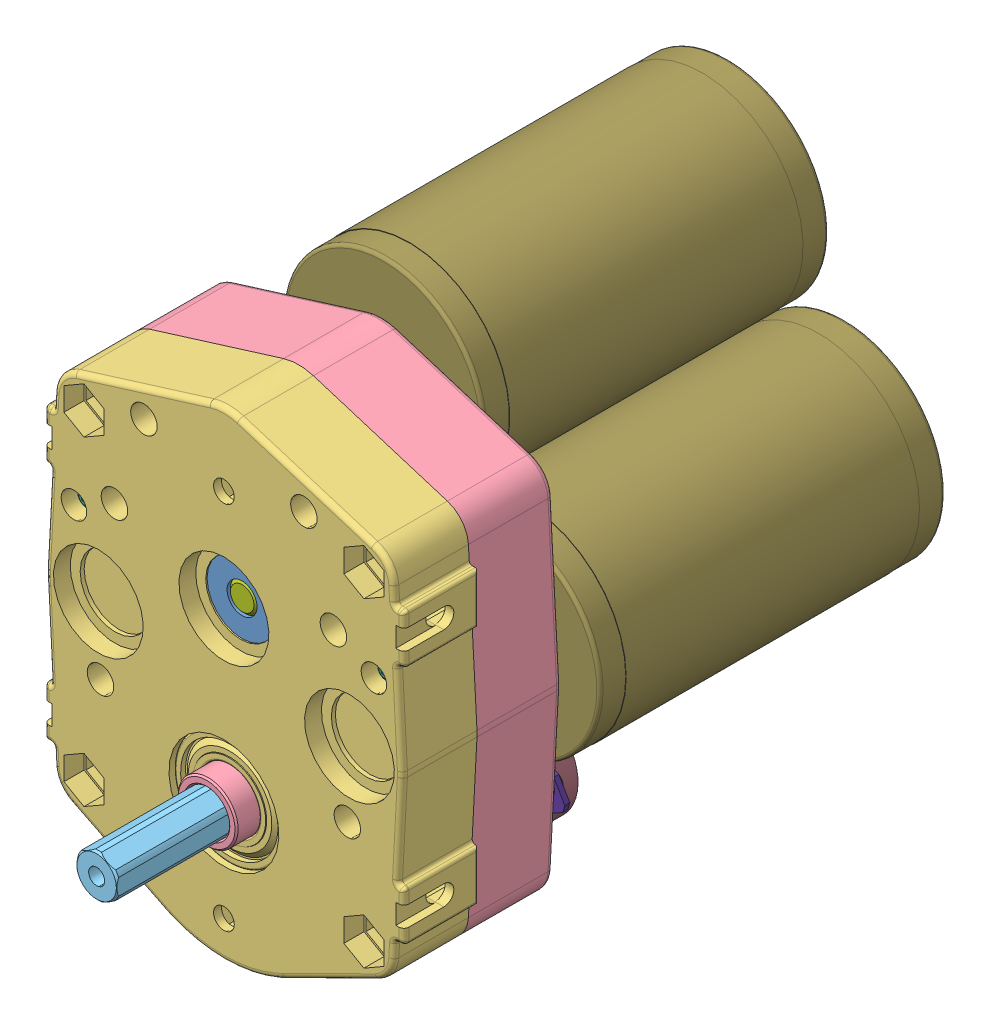
SolidWorks assembly 217-3195-STEP-20150102, configuration Default. Lengths in mm.
Overall size (143.3 175.36 205.56).
77 component instances, 44 part files, 0 mates.
Components (placement in the parent):
- 217-2733-001 Rev2-1: 217-2733-001 Rev2 [Default] at (0 53.4162 37.6682) x (0 0 1) z (-0.00054 -1 0) size (7.11 24.61 24.61)
- 217-2733-001 Rev2-2: 217-2733-001 Rev2 [Default] at (0 53.4162 7.9248) x (0 0 -1) z (-0.038475 0.99926 0) size (7.11 24.61 24.61)
- 217-2731-001 Rev2-1: 217-2731-001 Rev2 [Default] at (0 0 0.0381) x (-0.099212 0.995066 0) z (0.995066 0.099212 0) size (31.12 7.94 31.12)
- 217-2789-001 Rev2-1: 217-2789-001 Rev2 [Default] at (0 0 43.2943) x (0 0 -1) z (-0.58471 0.811243 0) size (11.1 38.4 38.4)
- 217-2778-001 Rev2_NCQ8A075-050M-1: 217-2778-001 Rev2_NCQ8A075-050M [Default] at (0 0 -53.848) x (-0.707107 0.707107 0) z (0 0 1) size (31.75 33.34 39.88)
  - 217-2778-NCQ8A075-050M_NCQ8 Tube_075A-1: 217-2778-NCQ8A075-050M_NCQ8 Tube_075A [Default] at origin size (31.75 33.34 26.92)
  - 217-2778-NCQ8A075-050M_NCQ8 Rod_075M-1: 217-2778-NCQ8A075-050M_NCQ8 Rod_075M [Default] at (0 0 -8.85) x (0.866025 -0.5 0) z (0 0 1) size (18.95 18.95 35.27)
  - 217-2778-NCQ8A075-050M_Snap Ring_075-1: 217-2778-NCQ8A075-050M_Snap Ring_075 [Default] at (0 0 10.362) size (21 20.74 0.97)
- 217-2428-012 Rev2-1: 217-2428-012 Rev2 [Default] at (0 0 -40.386) size (63.5 22.23 2.29)
- 217-2428-005 Rev1-1: 217-2428-005 Rev1 [Default] at (25.4 0 -19.05) x (-0.557362 -0.83027 0) z (-0.83027 0.557362 0) size (7.33 38.98 6.35)
- 217-2428-005 Rev1-2: 217-2428-005 Rev1 [Default] at (-25.4 0 -19.05) x (0.667436 0.744667 0) z (0.744667 -0.667436 0) size (7.33 38.98 6.35)
- SCREW-832-0375-1: SCREW-832-0375 [Default] at (25.4 0 -42.5958) x (0 0 1) z (-0.875404 0.483392 0) size (11.73 7.92 7.92)
- SCREW-832-0375-2: SCREW-832-0375 [Default] at (-25.4 0 -42.5958) x (0 0 1) z (-0.966319 0.257347 0) size (11.73 7.92 7.92)
- SCREW-832-0375-3: SCREW-832-0375 [Default] at (25.4 0 5.3848) x (0 0 -1) z (1 0 0) size (11.73 7.92 7.92)
- SCREW-832-0375-4: SCREW-832-0375 [Default] at (-25.4 0 5.3848) x (0 0 -1) z (0.941463 -0.337115 0) size (11.73 7.92 7.92)
- SBS1_SBS-0632-0250-1: SBS1_SBS-0632-0250 [Default] at (15.494 0 -36.2458) x (0 0 -1) z (0.854303 -0.519775 0) size (8.57 6.68 6.65)
- SBS1_SBS-0632-0250-2: SBS1_SBS-0632-0250 [Default] at (-15.494 0 -36.2458) x (0 0 -1) z (0.854303 -0.519775 0) size (8.57 6.68 6.65)
- 217-4098-100 Rev1-1: 217-4098-100 Rev1 [Default] at (0 0 -16.927) x (-0.503316 0.864103 0) z (0 0 1) size (18.03 19.79 22.46)
  - 217-4098-006 Rev2-1: 217-4098-006 Rev2 [Default] at (0 0 -4.6312) x (0 -1 0) z (0 0 -1) size (18.09 11.02 22.46)
  - 217-4098-006 Rev2-2: 217-4098-006 Rev2 [Default] at (0 0 -4.6312) x (0 1 0) z (0 0 -1) size (18.09 11.02 22.46)
  - 217-3489-001 Rev1-1: 217-3489-001 Rev1 [Default] at (0 0 -4.6312) x (0 0 1) z (-0.980217 -0.197926 0) size (4.77 12.7 12.7)
  - 97633A130_97633A130_grv-1: 97633A130_97633A130_grv [Default] at (0 0 -7.33) x (0 0 -1) z (0.979861 0.199683 0) size (0.64 8.74 7.34)
  - 91251A107_91251A107-1: 91251A107_91251A107 [Default] at (-4.8375 -6.735 -9.4343) x (0 0.863883 -0.503692) z (-1 0 0) size (4.65 4.65 10.79)
  - 91251A107_91251A107-2: 91251A107_91251A107 [Default] at (4.8375 6.735 -9.4343) x (0 0.470889 -0.882193) z (1 0 0) size (4.65 4.65 10.79)
- 217-2428-017 Rev2-1: 217-2428-017 Rev2 [Default] at (12.7 -21.997 -3.614) x (-0.578458 -0.815712 0) z (0 0 -1) size (14.73 14.73 7.37)
- 217-2428-016 Rev3_Spur01-1: 217-2428-016 Rev3_Spur01 [Default] at (0 0 -3.614) x (0.873157 -0.48744 0) z (0 0 1) size (40.67 40.74 13.32)
- 217-2428-019 Rev1-1: 217-2428-019 Rev1 [Default] at (12.7 -21.997 -20.6248) x (0.866025 0.5 0) z (0 0 1) size (50.8 19.05 1.57)
- 217-2428-006 Rev1-1: 217-2428-006 Rev1 [Default] at (32.079 -14.2875 -9.525) x (-0.752416 0.658689 0) z (0.658689 0.752416 0) size (7.33 19.93 6.35)
- 217-2428-006 Rev1-2: 217-2428-006 Rev1 [Default] at (-3.6662 -34.925 -9.525) x (0.84498 0.534798 0) z (0.534798 -0.84498 0) size (7.33 19.93 6.35)
- SCREW-832-0375-5: SCREW-832-0375 [Default] at (32.079 -14.2875 4.7498) x (0 0 -1) z (0.980613 0.195955 0) size (11.73 7.92 7.92)
- SCREW-832-0375-6: SCREW-832-0375 [Default] at (-3.6662 -34.925 5.3848) x (0 0 -1) z (-0.672515 -0.740083 0) size (11.73 7.92 7.92)
- SCREW-832-0375-7: SCREW-832-0375 [Default] at (-3.6662 -34.925 -22.8346) x (0 0 1) z (0.948865 0.315681 0) size (11.73 7.92 7.92)
- SCREW-832-0375-8: SCREW-832-0375 [Default] at (32.079 -14.2875 -22.8346) x (0 0 1) z (-0.875404 0.483392 0) size (11.73 7.92 7.92)
- 217-2614-001_12t-1: 217-2614-001_12t [Default] at (36.9798 39.6868 15.8623) x (-0.087156 0.996195 0) z (0 0 1) size (18.29 18.29 19)
- 217-2761-001 rev1-1: 217-2761-001 rev1 [Default] at (33.1943 39.3556 16.1) x (0.087156 -0.996195 0) z (0 0 1) size (2 2 20)
- 217-2761-001 rev1-2: 217-2761-001 rev1 [Default] at (-40.7653 40.018 16.1) x (0.087156 0.996195 0) z (0 0 1) size (2 2 20)
- 217-2614-001_12t-2: 217-2614-001_12t [Default] at (-36.9798 39.6868 15.8623) x (0.087156 0.996195 0) z (0 0 1) size (18.29 18.29 19)
- 217-2614-001_12t-3: 217-2614-001_12t [Default] at (0 92.8624 15.8623) x (0.97459 0.223996 0) z (0 0 1) size (18.29 18.29 19)
- 217-2761-001 rev1-3: 217-2761-001 rev1 [Default] at (-0.8512 96.5658 16.1) x (0.97459 0.223996 0) z (0 0 1) size (2 2 20)
- 217-3195-002 rev2-1: 217-3195-002 rev2 [Default] at (0 0 50.546) x (-1 0 0) z (0 0 -1) size (114.31 152.24 24.96)
- 217-3195-001 Rev1-1: 217-3195-001 Rev1 [Default] at origin size (113.41 152.24 26.86)
- 276-1027-001-1: 276-1027-001 [Default] at (47.625 58.1787 6.35) x (0 1 0) z (-1 0 0) size (8.61 5.64 9.94)
- 276-1027-001-2: 276-1027-001 [Default] at (-47.625 58.1787 6.35) x (0 -1 0) z (1 0 0) size (8.61 5.64 9.94)
- SCREW-832-1750-1: SCREW-832-1750 [Default] at (-47.625 58.1787 47.0408) x (0 0 -1) z (-0.960822 -0.277167 0) size (46.66 7.92 7.92)
- SCREW-832-1750-2: SCREW-832-1750 [Default] at (47.625 58.1787 47.0408) x (0 0 -1) z (-0.960822 -0.277167 0) size (46.66 7.92 7.92)
- 217-2428-004 Rev3-1: 217-2428-004 Rev3 [Default] at (0 53.4162 22.7711) x (-0.709585 0.70462 0) z (0 0 1) size (11 9.53 43.92)
- 217-2428-021 Rev1-1: 217-2428-021 Rev1 [Default] at (0 53.4162 9.5123) x (0.451333 -0.892356 0) z (0 0 1) size (15.88 15.88 3.17)
- 217-2428-029 Rev1-1: 217-2428-029 Rev1 [Default] at (0 53.4162 36.957) x (0.999846 0.017557 0) z (0 0 1) size (15.88 15.88 1.12)
- Grayhill Lock Washer-1: Grayhill Lock Washer [Default] at (12.7 -21.997 -18.6817) x (0.467173 -0.884166 0) z (0 0 1) size (19.69 19.69 0.74)
- Grayhill Nut-1: Grayhill Nut [Default] at (12.7 -21.997 -17.0434) x (0.984088 0.177684 0) z (0 0 1) size (18.33 15.88 2.54)
- 217-2000-1: 217-2000 [Default] at (0 92.8624 0) x (0 0 -1) z (0.223996 -0.97459 0) size (150.2 64.01 64.01)
- 217-2000-2: 217-2000 [Default] at (-36.9798 39.6868 0) x (0 0 -1) z (0.996195 -0.087156 0) size (150.2 64.01 64.01)
- 217-2000-3: 217-2000 [Default] at (36.9798 39.6868 0) x (0 0 -1) z (0.996195 0.087156 0) size (150.2 64.01 64.01)
- Grahill Encoder-1: Grahill Encoder [Default] at (12.7 -21.997 -16.1798) x (-0.580071 0.814566 0) z (-0.814566 -0.580071 0) size (31.75 31.12 31.75)
- 217-3210-001 Rev1_30t-1: 217-3210-001 Rev1_30t [Default] at (0 53.4162 30.0736) x (-0.966828 0.255427 0) z (0 0 1) size (41.01 41.12 12.65)
- 217-3291-001 Rev3-1: 217-3291-001 Rev3 [Default] at (0 0 0.0889) size (74.97 75.02 117.22)
  - 217-2428-008 Rev2-1: 217-2428-008 Rev2 [Default] at (0 0 10.2679) size (31.75 31.75 1.59)
  - 217-2428-028 Rev1_97633A250-1: 217-2428-028 Rev1_97633A250 [Default] at (0 0 37.1221) x (0 0 1) z (0.9357 -0.352797 0) size (1.07 23.39 21.18)
  - 217-2428-007 Rev1-1: 217-2428-007 Rev1 [Default] at (4.5085 7.809 14.2494) x (0.57515 -0.320306 -0.752732) z (-0.697826 0.288078 -0.655782) size (6.35 6.35 6.35)
  - 217-2428-007 Rev1-2: 217-2428-007 Rev1 [Default] at (3.1375 5.4343 26.9494) x (0.444163 0.822893 0.354354) z (0.803342 -0.540896 0.249144) size (6.35 6.35 6.35)
  - 217-3212-101 Rev1-1: 217-3212-101 Rev1 [Default] at (-7.461 13.6656 45.3224) x (0.998507 0.054615 0) z (0 0 -1) size (46.46 46.56 12.7)
    - 217-2428-022 Rev1-1: 217-2428-022 Rev1 [Default] at (6.7035 14.0527 24.6087) size (28.57 28.57 6.1)
    - 217-3212-001 Rev1_34t-1: 217-3212-001 Rev1_34t [Default] at (6.7035 14.0527 27.9107) size (46.46 46.56 11.11)
  - 217-3222-101 Rev1-1: 217-3222-101 Rev1 [Default] at (-16.5535 14.1005 52.7371) x (0.999887 0.015021 0) z (0 0 -1) size (73.87 73.92 12.7)
    - 217-2428-022 Rev1-1: 217-2428-022 Rev1 [Default] at (16.3398 14.3476 19.3234) size (28.57 28.57 6.1)
    - 217-3222-001 Rev1_Spur01-1: 217-3222-001 Rev1_Spur01 [Default] at (16.3398 14.3476 22.6254) x (0.999377 0.0353 0) z (0 0 1) size (71.39 71.45 11.11)
  - 217-4098-000 Rev2-1: 217-4098-000 Rev2 [Default] x (0 1 0) z (0 0 1) size (22.23 22.23 117.22)
    - 217-4098-005 Rev1_91612A226-1: 217-4098-005 Rev1_91612A226 [Default] at (0 0 46.2661) x (-0.144757 0 0.989467) z (0 -1 0) size (3.02 3.15 18.22)
    - 217-4098-003 Rev2-1: 217-4098-003 Rev2 [Default] x (1 0 0) z (0 0 -1) size (22.23 22.23 55.94)
    - 217-4098-002 Rev3-1: 217-4098-002 Rev3 [Default] at (0 0 62.9285) x (0 0 1) z (-1 0 0) size (59.88 12.73 14.67)
    - 217-4098-004 Rev1-1: 217-4098-004 Rev1 [Default] at (0 0 14.2494) x (-0.610335 0.792144 0) z (0 0 1) size (11.68 11.68 56)
  - 217-2428-007 Rev1-3: 217-2428-007 Rev1 [Default] at (4.355 -6.8759 14.2494) x (-0.564969 -0.337942 -0.752732) z (0.598396 0.460296 -0.655782) size (6.35 6.35 6.35)
  - 217-2428-007 Rev1-4: 217-2428-007 Rev1 [Default] at (-8.2857 0.5994 14.2494) x (-0.010182 0.658248 -0.752732) z (0.09943 -0.748374 -0.655782) size (6.35 6.35 6.35)
  - 217-2428-007 Rev1-5: 217-2428-007 Rev1 [Default] at (2.984 -4.5013 26.9494) x (0.490565 -0.796103 0.354354) z (-0.870101 -0.425267 0.249144) size (6.35 6.35 6.35)
  - 217-2428-007 Rev1-6: 217-2428-007 Rev1 [Default] at (-5.5437 0.5994 26.9494) x (-0.934728 -0.02679 0.354354) z (0.066759 0.966163 0.249144) size (6.35 6.35 6.35)
- 217-2711-002 Rev1_50t-1: 217-2711-002 Rev1_50t [Default] at (0 53.4162 17.4244) x (0.262208 -0.965011 0) z (0 0 1) size (66.7 66.76 12.65)
- 217-2428-023 Rev1_9714K3-1: 217-2428-023 Rev1_9714K3 [Default] at (0 0 37.7444) x (-0.089015 0.99603 0) z (0.99603 0.089015 0) size (26.82 4.09 28.39)
